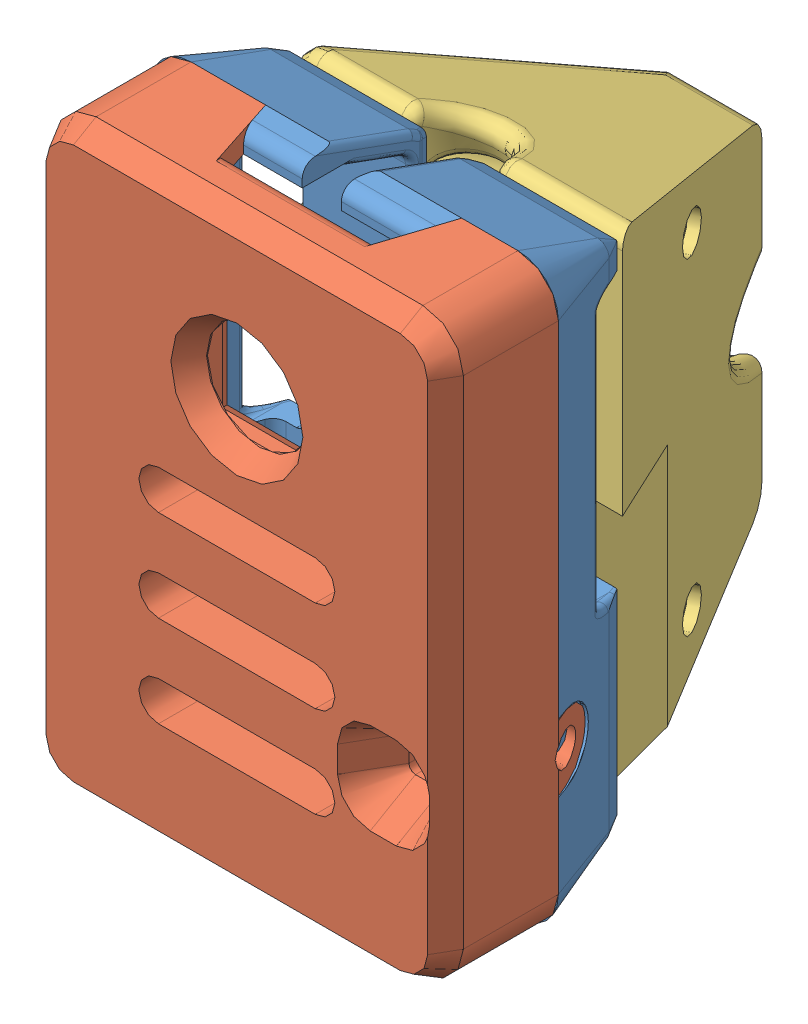
SolidWorks assembly AIThinkerEsp32CamCase, configuration Default. Lengths in mm.
Overall size (31.2 44.2 36.66).
3 component instances, 3 part files, 9 mates.
Components (placement in the parent):
- aiThinkerEsp32CamCase.Back-1: aiThinkerEsp32CamCase.Back [Default] at origin size (31.2 44.2 10)
- aiThinkerEsp32CamCase.Front-1: aiThinkerEsp32CamCase.Front [Default] at (0 0 16.5) size (31.2 44.2 12.6)
- aiThinkerEsp32CamCase.MountBlock-1: aiThinkerEsp32CamCase.MountBlock [Default] at origin size (25.43 39.14 20.06)
Mates (geometry in assembly coordinates):
- Coincident1: coincident aligned: plane of aiThinkerEsp32CamCase.Back-1 through (0 0 0) normal (1 0 0)
- Coincident2: coincident aligned: plane of aiThinkerEsp32CamCase.Back-1 through (0 0 0) normal (0 1 0)
- Coincident3: coincident aligned: plane of aiThinkerEsp32CamCase.Back-1 through (0 0 0) normal (0 0 1)
- Coincident4: coincident aligned: plane of aiThinkerEsp32CamCase.Front-1 through (0 0 16.5) normal (0 1 0)
- Coincident5: coincident aligned: plane of aiThinkerEsp32CamCase.Front-1 through (0 0 16.5) normal (1 0 0)
- LimitDistance1: limit distance = 0 mm anti-aligned: plane of aiThinkerEsp32CamCase.Back-1 through (-12.5 -19 7.5) normal (0 0 1); plane of aiThinkerEsp32CamCase.Front-1 through (12.5 19 7.5) normal (0 0 -1)
- Concentric1: concentric anti-aligned: circle of aiThinkerEsp32CamCase.Back-1; circle of aiThinkerEsp32CamCase.SideMount-1
- Parallel1: parallel aligned: plane of aiThinkerEsp32CamCase.SideMount-1 through (0 0 0) normal (1 0 0)
- LimitDistance2: limit distance = 0 mm anti-aligned: plane of aiThinkerEsp32CamCase.Back-1 through (-12.5 -19 0) normal (0 0 -1); plane of aiThinkerEsp32CamCase.SideMount-1 through (0 0 0) normal (0 0 1)
